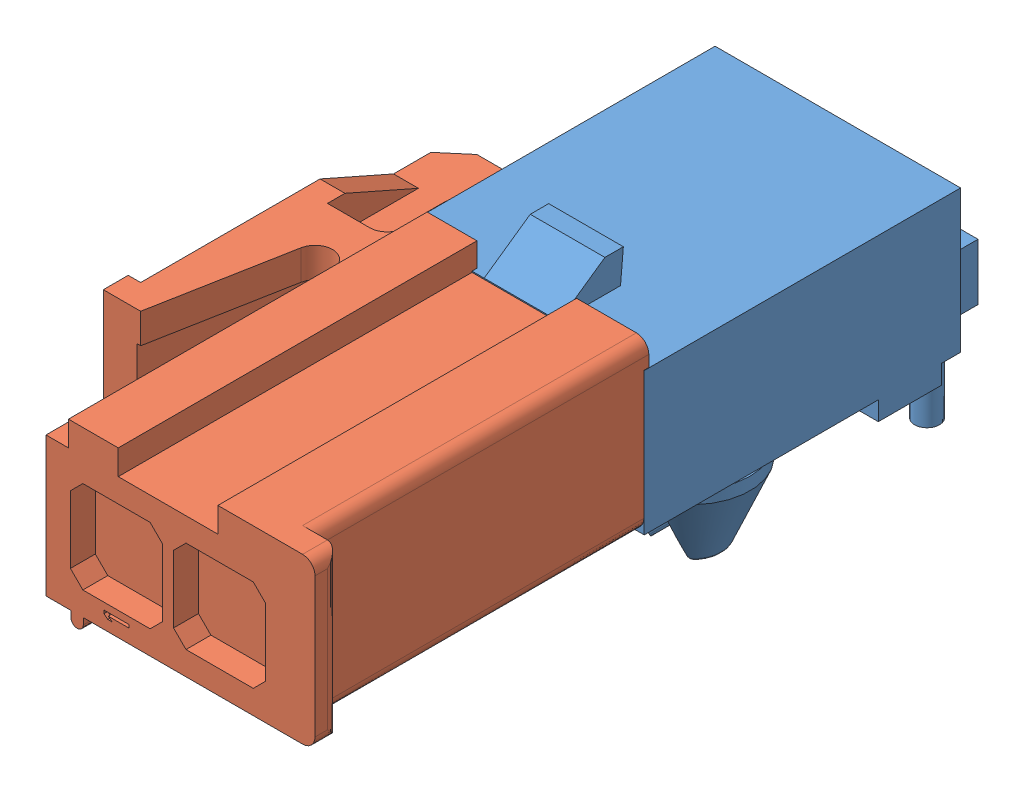
SolidWorks assembly 1-770966-0 ASM, configuration Default. Lengths in mm.
Overall size (14.7 13.01 28.91).
2 component instances, 2 part files, 3 mates.
Components (placement in the parent):
- c-1-770966-0-d-3d-1: c-1-770966-0-d-3d [Default] at (17.2792 -2.4515 1.8486) size (11.15 13.01 14.71)
- c-172165-1-h-3d-1: c-172165-1-h-3d [Default] at (17.2919 -2.4515 -7.651) x (0 -1 0) z (0 0 -1) size (7.1 14.7 23.7)
Mates (geometry in assembly coordinates):
- Width2: width aligned: plane of c-1-770966-0-d-3d-1 through (13.4438 -0.6735 1.8486) normal (1 0 0); plane of c-172165-1-h-3d-1 through (21.14 -3.2389 1.8486) normal (-1 0 0); plane of c-1-770966-0-d-3d-1 through (21.0869 -1.7265 1.649) normal (1 0 0); plane of c-172165-1-h-3d-1 through (13.4969 -4.1765 1.649) normal (-1 0 0)
- Width3: width anti-aligned: plane of c-1-770966-0-d-3d-1 through (20.1494 -0.6735 1.8486) normal (0 -1 0); plane of c-172165-1-h-3d-1 through (17.584 -4.2295 1.8486) normal (0 1 0); plane of c-1-770966-0-d-3d-1 through (17.6369 -0.7265 1.649) normal (0 1 0); plane of c-172165-1-h-3d-1 through (20.0869 -4.1765 1.649) normal (0 -1 0)
- Coincident1: coincident anti-aligned: plane of c-1-770966-0-d-3d-1 through (17.2792 -2.4515 -7.651) normal (0 0 1); plane of c-172165-1-h-3d-1 through (17.2919 1.3485 -7.651) normal (0 0 -1)
